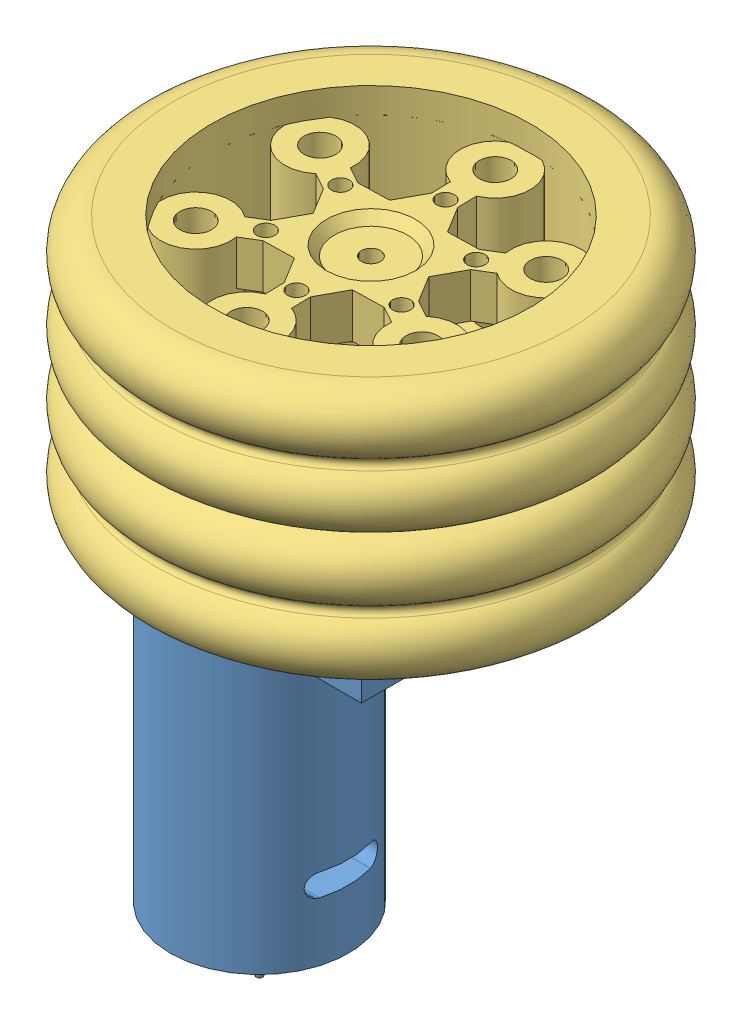
SolidWorks assembly 002-电机模组, configuration 电机模组. Lengths in mm.
Overall size (73.78 112 73.78).
4 component instances, 3 part files, 8 mates.
Components (placement in the parent):
- 002-电机-1: 002-电机 [电机] at (-76.4531 13.5239 67) size (47 82 30)
- 002-联轴器-1: 002-联轴器 [联轴器] at (-42.9531 37.5239 82) x (0 -1 0) z (-0.87829 0 -0.478128) size (10 12 13.86)
- 002-轮子-1: 002-轮子 [轮子] at (-42.9531 35.5239 82) x (0.999686 0 -0.025074) z (0 1 0) size (72 72 20)
- 002-轮子-2: 002-轮子 [轮子] at (-42.9531 55.5239 82) x (0.999686 0 -0.025074) z (0 1 0) size (72 72 20)
Mates (geometry in assembly coordinates):
- 重合5: coincident anti-aligned: plane of 002-联轴器-1 through (-42.9531 37.5239 82) normal (0 1 0); plane of 002-轮子-1 through (-42.9531 37.5239 82) normal (0 -1 0)
- 宽度5: width anti-aligned: plane of 002-轮子-1 through (-42.7793 37.5239 88.926) normal (0.478128 0 -0.87829); plane of 002-联轴器-1 through (-43.1268 37.5239 75.074) normal (-0.478128 0 0.87829); plane of 002-轮子-1 through (-42.7793 27.5239 88.926) normal (-0.478128 0 0.87829); plane of 002-联轴器-1 through (-43.1268 27.5239 75.074) normal (0.478128 0 -0.87829)
- 宽度6: width anti-aligned: plane of 002-联轴器-1 through (-37.0418 27.5239 78.3865) normal (0.999686 0 -0.025074); plane of 002-轮子-1 through (-48.8643 27.5239 85.6135) normal (-0.999686 0 0.025074); plane of 002-联轴器-1 through (-37.0418 37.5239 78.3865) normal (-0.999686 0 0.025074); plane of 002-轮子-1 through (-48.8643 37.5239 85.6135) normal (0.999686 0 -0.025074)
- 同心2: concentric aligned: cylinder of 002-轮子-1 through (-42.9531 25.5239 82) axis (0 1 0) radius 1.5; cylinder of 002-轮子-2 through (-42.9531 45.5239 82) axis (0 1 0) radius 1.5
- 重合6: coincident anti-aligned: plane of 002-轮子-1 through (-17.9609 45.5239 81.3731) normal (0 1 0); plane of 002-轮子-2 through (-17.9609 45.5239 81.3731) normal (0 -1 0)
- 同心3: concentric aligned: cylinder of 002-轮子-1 through (-25.3873 25.5239 91.5626) axis (0 1 0) radius 2.5; cylinder of 002-轮子-2 through (-25.3873 45.5239 91.5626) axis (0 1 0) radius 2.5
- 同心4: concentric aligned: cylinder of 002-电机-1 through (-42.9531 27.5239 82) axis (0 1 0) radius 1.5; cylinder of 002-轮子-2 through (-42.9531 45.5239 82) axis (0 1 0) radius 1.5
- 重合7: coincident anti-aligned: plane of 002-电机-1 through (-42.9531 27.5239 82) normal (0 1 0); plane of 002-联轴器-1 through (-42.9531 27.5239 82) normal (0 -1 0)
